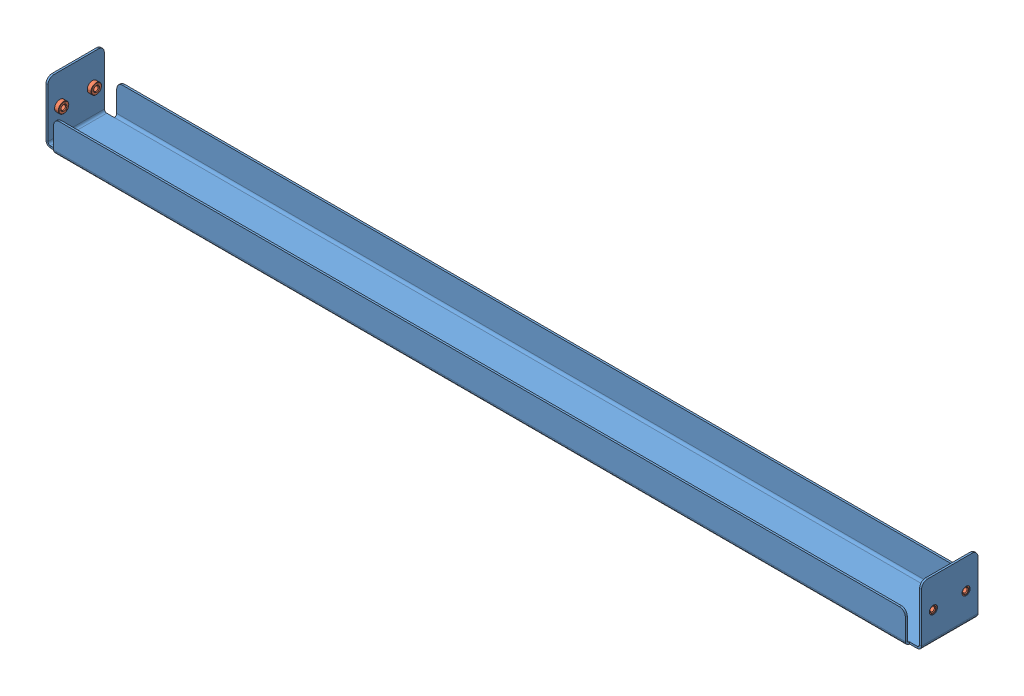
SolidWorks assembly GE-20303, configuration Default. Lengths in mm.
Overall size (935.74 63.5 69.51).
5 component instances, 2 part files, 8 mates.
Components (placement in the parent):
- GE-20303-01-1: GE-20303-01 [Default] at origin size (935.74 63.5 69.51)
- S-0420-1ZI-PennEngineering-1: S-0420-1ZI-PennEngineering [Default] at (0.6807 29.6977 -47.625) size (5.69 11.18 11.18)
- S-0420-1ZI-PennEngineering-2: S-0420-1ZI-PennEngineering [Default] at (0.6807 29.6977 -12.7) x (1 0 0) z (0 -0.158553 0.987351) size (5.69 11.18 11.18)
- S-0420-1ZI-PennEngineering-4: S-0420-1ZI-PennEngineering [Default] at (935.0553 29.6977 -47.625) x (-1 0 0) z (0 0.939693 -0.34202) size (5.69 11.18 11.18)
- S-0420-1ZI-PennEngineering-6: S-0420-1ZI-PennEngineering [Default] at (935.0553 29.6977 -12.7) x (-1 0 0) z (0 0.866025 -0.5) size (5.69 11.18 11.18)
Mates (geometry in assembly coordinates):
- Concentric1: concentric anti-aligned: circle of brace-1; circle of S-0420-1ZI-PennEngineering-1
- Coincident1: coincident anti-aligned: plane of GE-20303-01-1 through (2.0523 0 0) normal (1 0 0); plane of S-0420-1ZI-PennEngineering-1 through (2.0523 29.6977 -44.831) normal (-1 0 0)
- Concentric2: concentric anti-aligned: circle of brace-1; circle of S-0420-1ZI-PennEngineering-2
- Coincident2: coincident anti-aligned: plane of GE-20303-01-1 through (2.0523 0 0) normal (1 0 0); plane of S-0420-1ZI-PennEngineering-2 through (2.0523 29.2547 -9.9413) normal (-1 0 0)
- Concentric3: concentric anti-aligned: circle of brace-1; circle of S-0420-1ZI-PennEngineering-4
- Coincident3: coincident anti-aligned: plane of GE-20303-01-1 through (933.6837 0 0) normal (-1 0 0); plane of S-0420-1ZI-PennEngineering-4 through (933.6837 32.3232 -48.5806) normal (1 0 0)
- Concentric4: concentric anti-aligned: circle of brace-1; circle of S-0420-1ZI-PennEngineering-6
- Coincident4: coincident anti-aligned: plane of GE-20303-01-1 through (933.6837 0 0) normal (-1 0 0); plane of S-0420-1ZI-PennEngineering-6 through (933.6837 32.1174 -14.097) normal (1 0 0)
